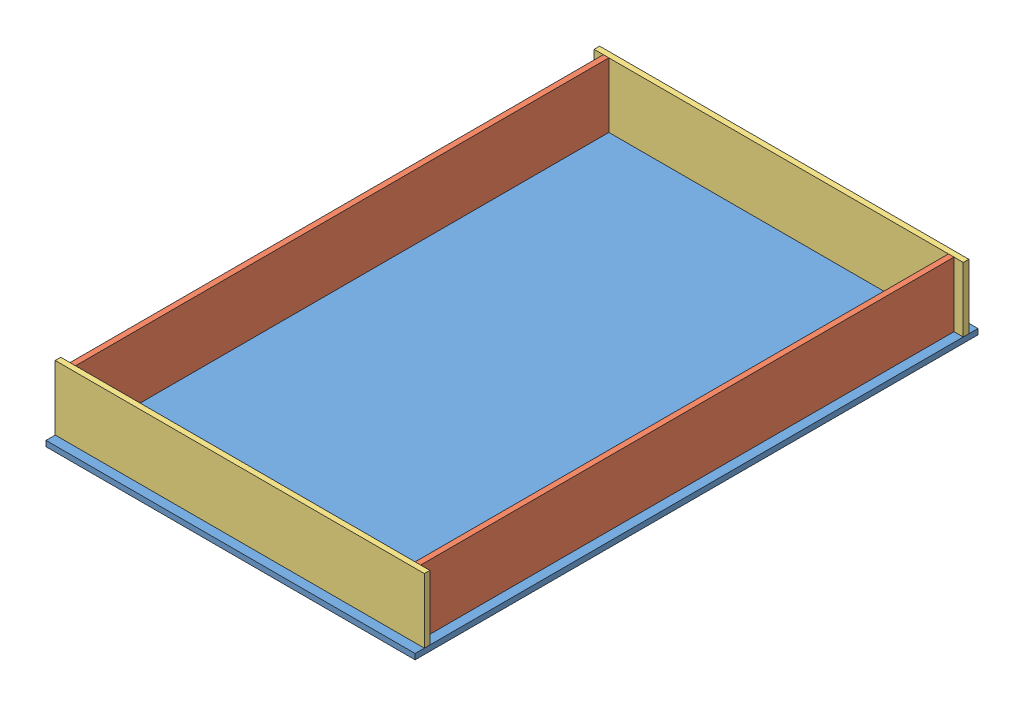
SolidWorks assembly Assem1, configuration Default. Lengths in mm.
Overall size (200 38 305).
5 component instances, 3 part files, 12 mates.
Components (placement in the parent):
- base-1: base [Default] at (16.4212 149.2181 390.9951) size (200 3 305)
- long_side-1: long_side [Default] at (21.4212 152.2181 382.9951) size (3 38 289)
- side-1: side [Default] at (16.4212 152.2181 90.9951) x (1 0 0) z (0 -1 0) size (200 3 38)
- long_side-2: long_side [Default] at (208.4212 152.2181 382.9951) size (3 38 289)
- side-2: side [Default] at (16.4212 152.2181 382.9951) x (1 0 0) z (0 -1 0) size (200 3 38)
Mates (geometry in assembly coordinates):
- Coincident2: coincident anti-aligned: plane of base-1 through (156.4212 142.2181 90.9951) normal (0 0 1); plane of side-1 through (16.4212 152.2181 90.9951) normal (0 0 -1)
- Coincident3: coincident aligned: plane of base-1 through (216.4212 152.2181 390.9951) normal (1 0 0); plane of side-1 through (216.4212 152.2181 93.9951) normal (1 0 0)
- Coincident4: coincident anti-aligned: plane of base-1 through (16.4212 152.2181 390.9951) normal (0 1 0); plane of side-1 through (196.4212 152.2181 93.9951) normal (0 -1 0)
- Coincident5: coincident anti-aligned: plane of base-1 through (24.4212 142.2181 460.9951) normal (-1 0 0); plane of long_side-1 through (24.4212 152.2181 382.9951) normal (1 0 0)
- Coincident6: coincident anti-aligned: plane of long_side-1 through (24.4212 152.2181 93.9951) normal (0 0 -1); plane of side-1 through (16.4212 152.2181 93.9951) normal (0 0 1)
- Coincident7: coincident aligned: plane of base-1 through (16.4212 149.2181 390.9951) normal (0 -1 0); plane of long_side-1 through (24.4212 149.2181 370.9951) normal (0 -1 0)
- Coincident9: coincident aligned: plane of base-1 through (216.4212 152.2181 390.9951) normal (1 0 0); plane of side-2 through (216.4212 152.2181 385.9951) normal (1 0 0)
- Coincident11: coincident aligned: plane of base-1 through (16.4212 149.2181 390.9951) normal (0 -1 0); plane of side-2 through (71.4212 149.2181 385.9951) normal (0 -1 0)
- Coincident12: coincident anti-aligned: plane of base-1 through (156.4212 142.2181 382.9951) normal (0 0 1); plane of side-2 through (16.4212 152.2181 382.9951) normal (0 0 -1)
- Coincident13: coincident anti-aligned: plane of base-1 through (211.4212 142.2181 530.9951) normal (-1 0 0); plane of long_side-2 through (211.4212 152.2181 382.9951) normal (1 0 0)
- Coincident14: coincident aligned: plane of base-1 through (16.4212 149.2181 390.9951) normal (0 -1 0); plane of long_side-2 through (211.4212 149.2181 125.9951) normal (0 -1 0)
- Coincident15: coincident anti-aligned: plane of side-1 through (16.4212 152.2181 93.9951) normal (0 0 1); plane of long_side-2 through (211.4212 152.2181 93.9951) normal (0 0 -1)
